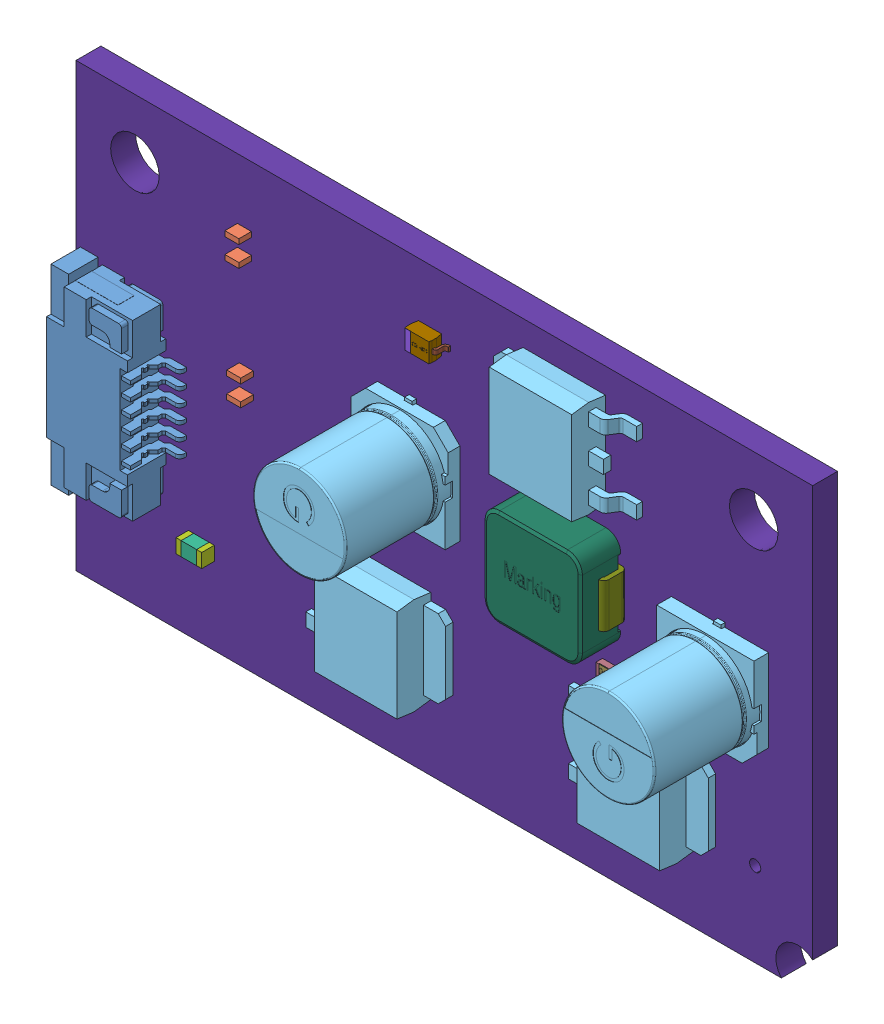
SolidWorks assembly torqueDriver, configuration 默认. Lengths in mm.
Overall size (50 30 11.69).
169 component instances, 35 part files, 0 mates.
Components (placement in the parent):
- _-1: _ [默认] at origin size (6.8 13 2.8)
  - ffc_fpc_affc20-06-100-shb-t-1: ffc_fpc_affc20-06-100-shb-t [默认] at (0.693 13.081 0.1) x (0 -1 0) z (-1 0 0) size (13 2.8 6.8)
- C2-1: C2 [默认] at origin size (0.95 1.75 0.85)
  - 6241791616-1: 6241791616 [默认] at (11.43 25.019 0) (suppressed, hidden)
  - 6241792176-1: 6241792176 [默认] at (11.43 24.319 0) size (0.95 0.35 0.85)
    - Extruded-1-1: Extruded-1 [默认] at origin size (0.95 0.35 0.85)
  - 6241792176-2: 6241792176 [默认] at (11.43 25.719 0) size (0.95 0.35 0.85)
    - Extruded-1-1: Extruded-1 [默认] at origin size (0.95 0.35 0.85)
- C3-1: C3 [默认] at origin size (0.95 1.75 0.85)
  - 6241791616-1: 6241791616 [默认] at (11.557 16.891 0) (suppressed, hidden)
  - 6241792176-1: 6241792176 [默认] at (11.557 16.191 0) size (0.95 0.35 0.85)
    - Extruded-1-1: Extruded-1 [默认] at origin size (0.95 0.35 0.85)
  - 6241792176-2: 6241792176 [默认] at (11.557 17.591 0) size (0.95 0.35 0.85)
    - Extruded-1-1: Extruded-1 [默认] at origin size (0.95 0.35 0.85)
- C4-1: C4 [默认] at origin size (1.8 3.4 1.35)
  - 6241790576-1: 6241790576 [默认] at (18.923 18.595 -3.0414) size (1.8 0.5 1.35)
    - Extruded-2-1: Extruded-2 [默认] at origin size (1.8 0.5 1.35)
  - 6241790576-2: 6241790576 [默认] at (18.923 15.695 -3.0414) size (1.8 0.5 1.35)
    - Extruded-2-1: Extruded-2 [默认] at origin size (1.8 0.5 1.35)
  - 6241790896-1: 6241790896 [默认] at (18.923 17.145 -3.0414) size (1.8 2.4 1.35)
    - Extruded-3-1: Extruded-3 [默认] at origin size (1.8 2.4 1.35)
- C7-1: C7 [默认] at origin size (6.6 7 7.7)
  - SL-G-1: SL-G [默认] at (22.8601 18.1609 0) x (0 -1 0) z (0 0 1) size (7 6.6 7.7)
    - SL-G-1: SL-G [默认] at origin size (7 6.6 7.7)
- C8-1: C8 [默认] at origin size (0.95 1.75 0.85)
  - 6241791616-1: 6241791616 [默认] at (39.37 19.304 -2.5414) (suppressed, hidden)
  - 6241792176-1: 6241792176 [默认] at (39.37 20.004 -2.5414) size (0.95 0.35 0.85)
    - Extruded-1-1: Extruded-1 [默认] at origin size (0.95 0.35 0.85)
  - 6241792176-2: 6241792176 [默认] at (39.37 18.604 -2.5414) size (0.95 0.35 0.85)
    - Extruded-1-1: Extruded-1 [默认] at origin size (0.95 0.35 0.85)
- C10-1: C10 [默认] at origin size (1.75 0.95 0.85)
  - 6241789056-1: 6241789056 [默认] at (32.639 15.494 -2.5414) size (1.05 0.95 0.85)
    - Extruded-4-1: Extruded-4 [默认] at origin size (1.05 0.95 0.85)
  - 6241789456-1: 6241789456 [默认] at (33.339 15.494 -2.5414) size (0.35 0.95 0.85)
    - Extruded-5-1: Extruded-5 [默认] at origin size (0.35 0.95 0.85)
  - 6241789456-2: 6241789456 [默认] at (31.939 15.494 -2.5414) size (0.35 0.95 0.85)
    - Extruded-5-1: Extruded-5 [默认] at origin size (0.35 0.95 0.85)
- D1-1: D1 [默认] at origin size (2.6 1.3 1)
  - D1-subassembly-1-1: D1-subassembly-1 [默认] at (13.7161 21.5899 -1.6914) x (1 0 0) z (0 0 -1) size (2.6 1.3 1)
    - SOD-323-1: SOD-323 [默认] at origin size (0.4 1.3 0.01)
    - SOD-323-1-1: SOD-323-1 [默认] at origin size (1.7 1.3 0.9)
    - SOD-323-2-1: SOD-323-2 [默认] at origin size (0.45 0.3 0.8)
    - SOD-323-3-1: SOD-323-3 [默认] at origin size (0.45 0.3 0.8)
- D2-1: D2 [默认] at origin size (2.6 1.3 1)
  - D2-subassembly-1-1: D2-subassembly-1 [默认] at (13.4621 13.5889 -1.6914) x (1 0 0) z (0 0 -1) size (2.6 1.3 1)
    - SOD-323-1: SOD-323 [默认] at origin size (0.4 1.3 0.01)
    - SOD-323-1-1: SOD-323-1 [默认] at origin size (1.7 1.3 0.9)
    - SOD-323-2-1: SOD-323-2 [默认] at origin size (0.45 0.3 0.8)
    - SOD-323-3-1: SOD-323-3 [默认] at origin size (0.45 0.3 0.8)
- D3-1: D3 [默认] at origin size (2.6 1.3 1)
  - D3-subassembly-1-1: D3-subassembly-1 [默认] at (24.1299 25.7809 0) x (-1 0 0) z (0 0 1) size (2.6 1.3 1)
    - SOD-323-1: SOD-323 [默认] at origin size (0.4 1.3 0.01)
    - SOD-323-1-1: SOD-323-1 [默认] at origin size (1.7 1.3 0.9)
    - SOD-323-2-1: SOD-323-2 [默认] at origin size (0.45 0.3 0.8)
    - SOD-323-3-1: SOD-323-3 [默认] at origin size (0.45 0.3 0.8)
- IC1-1: IC1 [默认] at origin size (6 4.9 1.75)
  - 6132017696-1: 6132017696 [默认] at (12.319 25.908 -1.6914) x (1 0 0) z (0 0 -1) size (6 4.9 1.75)
    - 6132017696-subassembly-1-1: 6132017696-subassembly-1 [默认] at origin size (6 4.22 1)
      - PinsArrayLR-1: PinsArrayLR [默认] at origin size (1.05 0.41 1)
      - PinsArrayLR-1-1: PinsArrayLR-1 [默认] at origin size (1.05 0.41 1)
      - PinsArrayLR-2-1: PinsArrayLR-2 [默认] at origin size (1.05 0.41 1)
      - PinsArrayLR-3-1: PinsArrayLR-3 [默认] at origin size (1.05 0.41 1)
      - PinsArrayLR-4-1: PinsArrayLR-4 [默认] at origin size (1.05 0.41 1)
      - PinsArrayLR-5-1: PinsArrayLR-5 [默认] at origin size (1.05 0.41 1)
      - PinsArrayLR-6-1: PinsArrayLR-6 [默认] at origin size (1.05 0.41 1)
      - PinsArrayLR-7-1: PinsArrayLR-7 [默认] at origin size (1.05 0.41 1)
    - Body-1: Body [默认] at origin size (3.9 4.9 1.57)
- IC2-1: IC2 [默认] at origin size (6 4.9 1.75)
  - 6132017696-1: 6132017696 [默认] at (12.491 17.78 -1.6914) x (1 0 0) z (0 0 -1) size (6 4.9 1.75)
    - 6132017696-subassembly-1-1: 6132017696-subassembly-1 [默认] at origin size (6 4.22 1)
      - PinsArrayLR-1: PinsArrayLR [默认] at origin size (1.05 0.41 1)
      - PinsArrayLR-1-1: PinsArrayLR-1 [默认] at origin size (1.05 0.41 1)
      - PinsArrayLR-2-1: PinsArrayLR-2 [默认] at origin size (1.05 0.41 1)
      - PinsArrayLR-3-1: PinsArrayLR-3 [默认] at origin size (1.05 0.41 1)
      - PinsArrayLR-4-1: PinsArrayLR-4 [默认] at origin size (1.05 0.41 1)
      - PinsArrayLR-5-1: PinsArrayLR-5 [默认] at origin size (1.05 0.41 1)
      - PinsArrayLR-6-1: PinsArrayLR-6 [默认] at origin size (1.05 0.41 1)
      - PinsArrayLR-7-1: PinsArrayLR-7 [默认] at origin size (1.05 0.41 1)
    - Body-1: Body [默认] at origin size (3.9 4.9 1.57)
- IC3-1: IC3 [默认] at origin size (4.93 3 1.1)
  - 6132016496-1: 6132016496 [默认] at (8.763 6.223 -2.3814) x (0 1 0) z (-1 0 0) size (3 1.1 4.93)
    - LEAD-SO-1: LEAD-SO [默认] at (-1 -0.44 -1.9) x (-1 0 0) z (0 0 -1) size (0.22 0.69 0.96)
    - LEAD-SO-2: LEAD-SO [默认] at (0 -0.44 1.9) size (0.22 0.69 0.96)
    - LEAD-SO-3: LEAD-SO [默认] at (-0.5 -0.44 -1.9) x (-1 0 0) z (0 0 -1) size (0.22 0.69 0.96)
    - LEAD-SO-4: LEAD-SO [默认] at (1 -0.44 -1.9) x (-1 0 0) z (0 0 -1) size (0.22 0.69 0.96)
    - LEAD-SO-5: LEAD-SO [默认] at (0.5 -0.44 -1.9) x (-1 0 0) z (0 0 -1) size (0.22 0.69 0.96)
    - LEAD-SO-6: LEAD-SO [默认] at (0 -0.44 -1.9) x (-1 0 0) z (0 0 -1) size (0.22 0.69 0.96)
    - LEAD-SO-7: LEAD-SO [默认] at (-0.5 -0.44 1.9) size (0.22 0.69 0.96)
    - LEAD-SO-8: LEAD-SO [默认] at (1 -0.44 1.9) size (0.22 0.69 0.96)
    - LEAD-SO-9: LEAD-SO [默认] at (-1 -0.44 1.9) size (0.22 0.69 0.96)
    - LEAD-SO-10: LEAD-SO [默认] at (0.5 -0.44 1.9) size (0.22 0.69 0.96)
    - BODY-SO-1: BODY-SO [默认] at origin size (3 1 3)
- Q1-1: Q1 [默认] at origin size (9.6 6.6 2.3)
  - TO-252-3-1: TO-252-3 [默认] at (39.116 7.62 0) x (0 -1 0) z (0 0 1) size (6.6 9.6 2.3)
- Q2-1: Q2 [默认] at origin size (9.6 6.6 2.3)
  - TO-252-3-1: TO-252-3 [默认] at (39.116 7.62 -1.6914) x (0 1 0) z (0 0 -1) size (6.6 9.6 2.3)
- Q3-1: Q3 [默认] at origin size (9.6 6.6 2.3)
  - TO-252-3-1: TO-252-3 [默认] at (21.2852 7.62 0) x (0 -1 0) z (0 0 1) size (6.6 9.6 2.3)
- Q4-1: Q4 [默认] at origin size (9.6 6.6 2.3)
  - TO-252-3-1: TO-252-3 [默认] at (21.2852 7.62 -1.6914) x (0 1 0) z (0 0 -1) size (6.6 9.6 2.3)
- Q5-1: Q5 [默认] at origin size (9.6 6.6 2.3)
  - TO-252-3-1: TO-252-3 [默认] at (33.147 25.146 0) x (0 1 0) z (0 0 1) size (6.6 9.6 2.3)
- R1-1: R1 [默认] at origin size (6.3 3.1 0.75)
  - 6132022016-1: 6132022016 [默认] at (8.763 10.033 -1.6914) x (1 0 0) z (0 0 -1) size (6.3 3.1 0.75)
    - body-1-1: body-1 [默认] at (-2.55 -1.519 0.0075) size (5.1 3.04 0.73)
    - term2-1: term2 [默认] at (2.55 -1.55 0) size (0.6 3.1 0.75)
    - term1-1: term1 [默认] at (-3.15 -1.55 0) size (0.6 3.1 0.75)
- R4-1: R4 [默认] at origin size (3.35 2.64 0.71)
  - 6241787936-1: 6241787936 [默认] at (37.719 24.511 -2.4014) size (2.35 2.64 0.1)
    - Extruded-6-1: Extruded-6 [默认] at origin size (2.35 2.64 0.1)
  - 6241788416-1: 6241788416 [默认] at (36.294 24.511 -2.4014) size (0.5 2.64 0.71)
    - Extruded-7-1: Extruded-7 [默认] at origin size (0.5 2.64 0.71)
  - 6241788416-2: 6241788416 [默认] at (39.144 24.511 -2.4014) size (0.5 2.64 0.71)
    - Extruded-7-1: Extruded-7 [默认] at origin size (0.5 2.64 0.71)
  - 6241788736-1: 6241788736 [默认] at (37.719 24.511 -2.3014) size (2.35 2.64 0.61)
    - Extruded-8-1: Extruded-8 [默认] at origin size (2.35 2.64 0.61)
- R6-1: R6 [默认] at origin size (1.6 0.8 0.45)
  - R6-subassembly-1-1: R6-subassembly-1 [默认] at (3.6831 15.4939 -1.6914) x (1 0 0) z (0 0 -1) size (1.6 0.8 0.45)
    - R0603-1: R0603 [默认] at origin size (1.2 0.8 0.05)
    - R0603-1-1: R0603-1 [默认] at origin size (1.6 0.8 0.45)
- R7-1: R7 [默认] at origin size (1.6 0.8 0.45)
  - R7-subassembly-1-1: R7-subassembly-1 [默认] at (3.6831 13.5889 -1.6914) x (1 0 0) z (0 0 -1) size (1.6 0.8 0.45)
    - R0603-1: R0603 [默认] at origin size (1.2 0.8 0.05)
    - R0603-1-1: R0603-1 [默认] at origin size (1.6 0.8 0.45)
- R8-1: R8 [默认] at origin size (1.6 0.8 0.45)
  - R8-subassembly-1-1: R8-subassembly-1 [默认] at (3.6831 17.3989 -1.6914) x (1 0 0) z (0 0 -1) size (1.6 0.8 0.45)
    - R0603-1: R0603 [默认] at origin size (1.2 0.8 0.05)
    - R0603-1-1: R0603-1 [默认] at origin size (1.6 0.8 0.45)
- RC1-1: RC1 [默认] at origin size (1.6 0.8 0.45)
  - RC1-subassembly-1-1: RC1-subassembly-1 [默认] at (36.5371 12.3191 0) x (1 0 0) z (0 0 1) size (1.6 0.8 0.45)
    - R0603-1: R0603 [默认] at origin size (1.2 0.8 0.05)
    - R0603-1-1: R0603-1 [默认] at origin size (1.6 0.8 0.45)
- RC2-1: RC2 [默认] at origin size (1.6 0.8 0.45)
  - RC2-subassembly-1-1: RC2-subassembly-1 [默认] at (36.5761 12.3189 -1.6914) x (1 0 0) z (0 0 -1) size (1.6 0.8 0.45)
    - R0603-1: R0603 [默认] at origin size (1.2 0.8 0.05)
    - R0603-1-1: R0603-1 [默认] at origin size (1.6 0.8 0.45)
- RC3-1: RC3 [默认] at origin size (1.6 0.8 0.45)
  - RC3-subassembly-1-1: RC3-subassembly-1 [默认] at (18.2879 12.3189 0) x (-1 0 0) z (0 0 1) size (1.6 0.8 0.45)
    - R0603-1: R0603 [默认] at origin size (1.2 0.8 0.05)
    - R0603-1-1: R0603-1 [默认] at origin size (1.6 0.8 0.45)
- RC4-1: RC4 [默认] at origin size (1.6 0.8 0.45)
  - RC4-subassembly-1-1: RC4-subassembly-1 [默认] at (20.0659 12.3191 -1.6914) x (-1 0 0) z (0 0 -1) size (1.6 0.8 0.45)
    - R0603-1: R0603 [默认] at origin size (1.2 0.8 0.05)
    - R0603-1-1: R0603-1 [默认] at origin size (1.6 0.8 0.45)
- U1-1: U1 [默认] at origin size (6.21 4.9 1.75)
  - SOIC8-1: SOIC8 [默认] at (33.528 19.431 -1.6914) x (0 -1 0) z (0 0 -1) size (4.9 6.21 1.75)
- L1-1: L1 [默认] at origin size (7.3 6.6 2.8)
  - WE-LHMI-7030_rev1-1: WE-LHMI-7030_rev1 [默认] at (33.7726 17.3228 0.1) size (7.3 6.6 2.8)
    - base-1: base [默认] at origin size (6.6 6.6 2.7)
    - pin-1: pin [默认] at origin size (7.3 3 1.6)
- C9-1: C9 [默认] at origin size (1.75 0.95 0.85)
  - 6241789056-1: 6241789056 [默认] at (8.509 5.715 0) size (1.05 0.95 0.85)
    - Extruded-4-1: Extruded-4 [默认] at origin size (1.05 0.95 0.85)
  - 6241789456-1: 6241789456 [默认] at (9.209 5.715 0) size (0.35 0.95 0.85)
    - Extruded-5-1: Extruded-5 [默认] at origin size (0.35 0.95 0.85)
  - 6241789456-2: 6241789456 [默认] at (7.809 5.715 0) size (0.35 0.95 0.85)
    - Extruded-5-1: Extruded-5 [默认] at origin size (0.35 0.95 0.85)
- C1-1: C1 [默认] at origin size (1.8 3.4 1.35)
  - 6241790576-1: 6241790576 [默认] at (18.923 26.977 -3.0414) size (1.8 0.5 1.35)
    - Extruded-2-1: Extruded-2 [默认] at origin size (1.8 0.5 1.35)
  - 6241790576-2: 6241790576 [默认] at (18.923 24.077 -3.0414) size (1.8 0.5 1.35)
    - Extruded-2-1: Extruded-2 [默认] at origin size (1.8 0.5 1.35)
  - 6241790896-1: 6241790896 [默认] at (18.923 25.527 -3.0414) size (1.8 2.4 1.35)
    - Extruded-3-1: Extruded-3 [默认] at origin size (1.8 2.4 1.35)
- C6-1: C6 [默认] at origin size (6.6 7 7.7)
  - SL-G-1: SL-G [默认] at (43.8149 15.4941 0) x (0 1 0) z (0 0 1) size (7 6.6 7.7)
    - SL-G-1: SL-G [默认] at origin size (7 6.6 7.7)
- Board-1: Board [默认] at origin size (50 30 1.69)
  - Board-Part-1-1: Board-Part-1 [默认] at (0 0 -1.6914) size (50 30 1.69)
